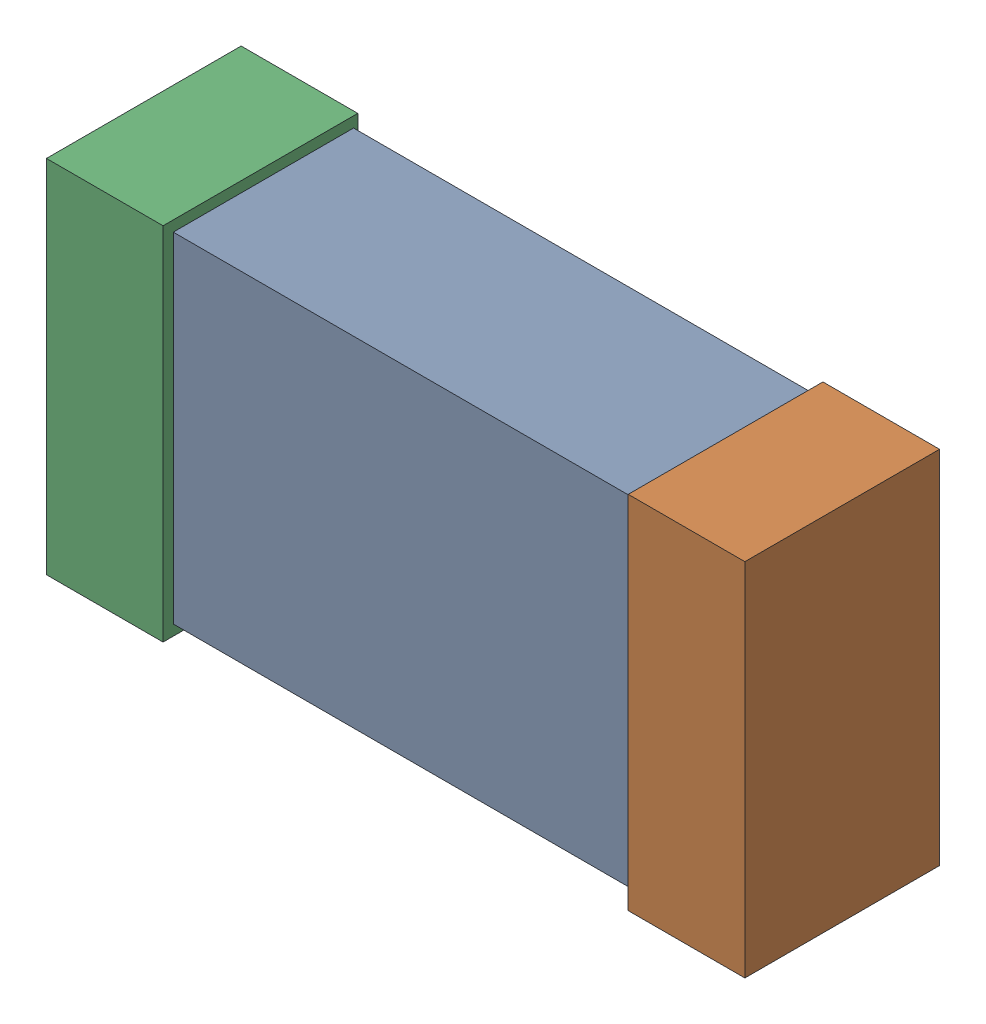
SolidWorks assembly R17, configuration Default. Lengths in mm.
Overall size (1.65 0.85 0.46).
6 component instances, 2 part files, 0 mates.
Components (placement in the parent):
- 432120720_20-1: 432120720_20 [Default] at (48.1003 13.7869 -0.8615) size (1.5 0.8 0.42)
  - Extruded (12)-1: Extruded (12) [Default] at origin size (1.5 0.8 0.42)
- 432120464_42-1: 432120464_42 [Default] at (48.7861 13.7869 -0.8715) size (0.28 0.85 0.46)
  - Extruded (11)-1: Extruded (11) [Default] at origin size (0.28 0.85 0.46)
- 432120464_43-1: 432120464_43 [Default] at (47.4146 13.7869 -0.8715) size (0.28 0.85 0.46)
  - Extruded (11)-1: Extruded (11) [Default] at origin size (0.28 0.85 0.46)
